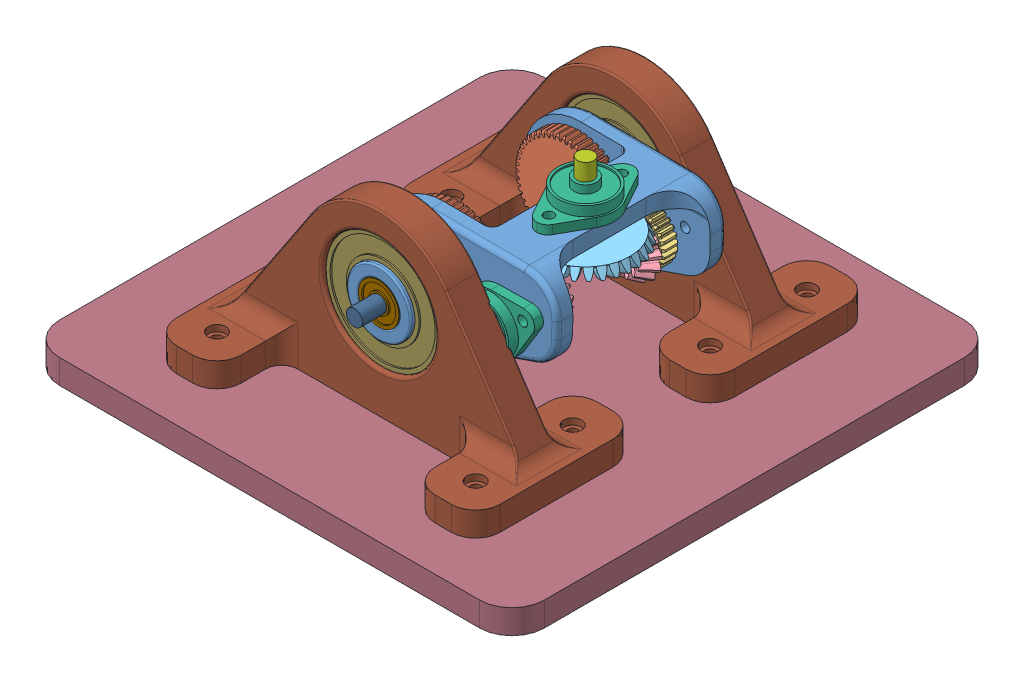
SolidWorks assembly ASSEMBLY Full Design 5th Attempt - Jaw Attach, configuration Default. Lengths in mm.
Overall size (300 144.17 300).
25 component instances, 13 part files, 62 mates.
Components (placement in the parent):
- Main Case-1: Main Case [Default] at (-15.1172 135.8372 30.5077) x (0.999965 -0.008399 0) z (0 0 1) size (115 70 165)
- Secondary Big Spur Gear-1: Secondary Big Spur Gear [Default] at (-15.1172 135.8372 45.5077) x (0.223812 0.974632 0) z (0 0 1) size (62.4 62.32 10)
- Secondary Big Spur Gear-2: Secondary Big Spur Gear [Default] at (-15.1172 135.8372 120.5077) x (-0.440646 0.897681 0) z (0 0 1) size (62.4 62.32 10)
- Main Spur Gear - Copy-1: Main Spur Gear - Copy [Default] at (29.8812 135.4592 120.5077) x (-0.557244 0.830349 0) z (0 0 1) size (32.38 32.33 10)
- Main Spur Gear - Copy-2: Main Spur Gear - Copy [Default] at (29.8812 135.4592 45.5077) x (-0.968851 0.247643 0) z (0 0 1) size (32.38 32.33 10)
- Secondary Bevel Gear-1: Secondary Bevel Gear [Default] at (29.8812 135.4592 53.1298) x (0.968851 -0.247643 0) z (-0.247643 -0.968851 0) size (38.46 39.84 38.26)
- Secondary Bevel Gear-2: Secondary Bevel Gear [Default] at (29.8812 135.4592 112.8856) x (-0.557244 0.830349 0) z (-0.830349 -0.557244 0) size (38.46 39.84 38.26)
- Secondary Main Bevel Gear-1: Secondary Main Bevel Gear [Default] at (30.0267 152.7791 83.0077) x (-0.999724 0.008397 -0.02196) z (-0.021959 0.000184 0.999759) size (61.95 69.28 62)
- Main Slewing Bearing-1: Main Slewing Bearing [Default] at (30.1752 170.458 83.0077) x (0 0 -1) z (0.999965 -0.008399 0) size (60 15.5 36)
- Secondary Gear Shaft-1: Secondary Gear Shaft [Default] at (30.3944 196.5599 83.0077) x (0.999724 -0.008397 0.02196) z (0.021959 -0.000184 -0.999759) size (10 46 10)
- Secondary Gear Shaft Horizontal-1: Secondary Gear Shaft Horizontal [Default] at (29.8812 135.4592 151.977) x (0.557244 -0.830349 0) z (0.830349 0.557244 0) size (10 46 10)
- Secondary Gear Shaft Horizontal-3: Secondary Gear Shaft Horizontal [Default] at (29.8812 135.4592 14.0383) x (-0.968851 0.247643 0) z (0.247643 0.968851 0) size (10 46 10)
- Main Slewing Bearing-2: Main Slewing Bearing [Default] at (29.8812 135.4592 30.5077) x (0.870194 0.492709 0) z (-0.492709 0.870194 0) size (60 15.5 36)
- Main Slewing Bearing-3: Main Slewing Bearing [Default] at (29.8812 135.4592 135.5077) x (0.870194 0.492709 0) z (0.492709 -0.870194 0) size (60 15.5 36)
- Main Bearing-1: Main Bearing [Default] at (-15.1172 135.8372 130.5077) size (25 25 10)
- Main Bearing-2: Main Bearing [Default] at (-15.1172 135.8372 35.5077) size (25 25 10)
- Secondary Gear Shaft Horizontal Back-1: Secondary Gear Shaft Horizontal Back [Default] at (-15.1172 135.8372 -14.4923) x (0.223812 0.974632 0) z (0.974632 -0.223812 0) size (10 65 10)
- Secondary Gear Shaft Horizontal Back-2: Secondary Gear Shaft Horizontal Back [Default] at (-15.1172 135.8372 180.5077) x (0.440646 -0.897681 0) z (0.897681 0.440646 0) size (10 65 10)
- Main Bearing-3: Main Bearing [Default] at (-15.1172 135.8372 160.5077) size (25 25 10)
- Main Bearing-4: Main Bearing [Default] at (-15.1172 135.8372 5.5077) x (0.957621 -0.288033 0) z (0 0 1) size (25 25 10)
- Main Holder-1: Main Holder [Default] at (-15.1172 135.8372 155.5077) size (200 110 100)
- Main Holder-2: Main Holder [Default] at (-15.1172 135.8372 10.5077) size (200 110 100)
- Main Bearing Big-1: Main Bearing Big [Default] at (-15.1172 135.8372 155.5077) size (70 70 15)
- Main Bearing Big-2: Main Bearing Big [Default] at (-15.1172 135.8372 10.5077) size (70 70 15)
- Bottom Plate-1: Bottom Plate [Default] at (-15.1172 60.8372 83.0077) x (0 0 1) z (-1 0 0) size (300 15 300)
Mates (geometry in assembly coordinates):
- Concentric1: concentric aligned: cylinder of Main Case-1 through (-15.1172 135.8372 125.5077) axis (0 0 1) radius 12.5; cylinder of Secondary Big Spur Gear-2 through (-15.1172 135.8372 115.5077) axis (0 0 1) radius 5
- Coincident1: coincident anti-aligned: plane of Main Case-1 through (-15.1172 135.8372 125.5077) normal (0 0 -1); plane of Secondary Big Spur Gear-2 through (-15.1172 135.8372 125.5077) normal (0 0 1)
- Concentric2: concentric anti-aligned: cylinder of Main Case-1 through (-15.1172 135.8372 40.5077) axis (0 0 -1) radius 12.5; cylinder of Secondary Big Spur Gear-1 through (-15.1172 135.8372 40.5077) axis (0 0 1) radius 5
- Coincident2: coincident anti-aligned: plane of Main Case-1 through (-15.1172 135.8372 40.5077) normal (0 0 1); plane of Secondary Big Spur Gear-1 through (-15.1172 135.8372 40.5077) normal (0 0 -1)
- Concentric3: concentric anti-aligned: cylinder of Main Case-1 through (29.8812 135.4592 40.5077) axis (0 0 -1) radius 5; cylinder of Main Spur Gear - Copy-2 through (29.8812 135.4592 40.5077) axis (0 0 1) radius 5
- Coincident3: coincident anti-aligned: plane of Main Case-1 through (-15.1172 135.8372 40.5077) normal (0 0 1); plane of Main Spur Gear - Copy-2 through (29.8812 135.4592 40.5077) normal (0 0 -1)
- GearMate1: gear = 60 : 30 mm: circle of Main Spur Gear - Copy-2; circle of Secondary Big Spur Gear-1
- Concentric5: concentric aligned: cylinder of Main Case-1 through (29.8812 135.4592 125.5077) axis (0 0 1) radius 5; cylinder of Main Spur Gear - Copy-1 through (29.8812 135.4592 115.5077) axis (0 0 1) radius 5
- Coincident4: coincident anti-aligned: plane of Main Case-1 through (-15.1172 135.8372 125.5077) normal (0 0 -1); plane of Main Spur Gear - Copy-1 through (29.8812 135.4592 125.5077) normal (0 0 1)
- GearMate2: gear = 60 : 30 mm: circle of Main Spur Gear - Copy-1; circle of Secondary Big Spur Gear-2
- Concentric7: concentric aligned: cylinder of Main Case-1 through (29.8812 135.4592 40.5077) axis (0 0 -1) radius 5; cylinder of Secondary Bevel Gear-1 through (29.8812 135.4592 62.5883) axis (0 0 -1) radius 5
- Coincident5: coincident aligned: plane of Main Spur Gear - Copy-2 through (30.0854 128.182 40.5077) normal (0.247643 0.968851 0); plane of Secondary Bevel Gear-1 through (26.21 129.1726 62.5883) normal (0.247643 0.968851 0)
- Concentric8: concentric aligned: cylinder of Main Spur Gear - Copy-1 through (29.8812 135.4592 115.5077) axis (0 0 1) radius 5; cylinder of Secondary Bevel Gear-2 through (29.8812 135.4592 103.4271) axis (0 0 1) radius 5
- Coincident6: coincident aligned: plane of Main Spur Gear - Copy-1 through (25.1833 129.8978 115.5077) normal (0.830349 0.557244 0); plane of Secondary Bevel Gear-2 through (25.1833 129.8978 103.4271) normal (0.830349 0.557244 0)
- Concentric9: concentric aligned: cylinder of Main Case-1 through (29.5872 100.4605 83.0077) axis (0.008399 0.999965 0) radius 5; cylinder of Secondary Main Bevel Gear-1 through (29.9744 146.5548 83.0077) axis (0.008399 0.999965 0) radius 5
- Coincident7: coincident: point of Secondary Bevel Gear-1; point of Secondary Main Bevel Gear-1
- Coincident8: coincident: line of Secondary Bevel Gear-2 through (29.8812 135.4592 83.0077) axis (0.278622 -0.415174 0.866025)
- GearMate3: gear = 34.5 : 60 mm: circle of Secondary Main Bevel Gear-1; circle of Secondary Bevel Gear-1
- GearMate4: gear = 60 : 34.5 mm: circle of Secondary Bevel Gear-2; circle of Secondary Main Bevel Gear-1
- Concentric11: concentric aligned: cylinder of Main Case-1 through (29.5872 100.4605 83.0077) axis (0.008399 0.999965 0) radius 5; cylinder of Main Slewing Bearing-1 through (30.1752 170.458 83.0077) axis (0.008399 0.999965 0) radius 5
- Concentric12: concentric anti-aligned: cylinder of Main Case-1 through (30.1752 170.458 60.5077) axis (0.008399 0.999965 0) radius 3; cylinder of Main Slewing Bearing-1 through (30.2214 175.9578 60.5077) axis (-0.008399 -0.999965 0) radius 3
- Coincident9: coincident anti-aligned: plane of Main Case-1 through (-14.8232 170.8359 40.5077) normal (0.008399 0.999965 0); plane of Main Slewing Bearing-1 through (30.1752 170.458 83.0077) normal (-0.008399 -0.999965 0)
- Concentric13: concentric aligned: cylinder of Main Slewing Bearing-1 through (30.1752 170.458 83.0077) axis (0.008399 0.999965 0) radius 5; cylinder of Secondary Gear Shaft-1 through (30.0081 150.5615 83.0077) axis (0.008399 0.999965 0) radius 5
- Coincident10: coincident aligned: plane of Secondary Main Bevel Gear-1 through (49.7552 150.3956 83.4415) normal (-0.008399 -0.999965 0); plane of Secondary Gear Shaft-1 through (30.0081 150.5615 83.0077) normal (-0.008399 -0.999965 0)
- Coincident11: coincident aligned: plane of Secondary Main Bevel Gear-1 through (31.8732 146.5388 87.6331) normal (-0.999724 0.008397 -0.02196); plane of Secondary Gear Shaft-1 through (32.0256 160.5449 86.0509) normal (-0.999724 0.008397 -0.02196)
- Concentric14: concentric aligned: cylinder of Secondary Bevel Gear-1 through (29.8812 135.4592 62.5883) axis (0 0 -1) radius 5; cylinder of Secondary Gear Shaft Horizontal-3 through (29.8812 135.4592 60.0383) axis (0 0 -1) radius 5
- Coincident12: coincident aligned: plane of Secondary Bevel Gear-1 through (20.9094 137.7525 60.0383) normal (0 0 1); plane of Secondary Gear Shaft Horizontal-3 through (29.8812 135.4592 60.0383) normal (0 0 1)
- Coincident15: coincident aligned: plane of Secondary Bevel Gear-1 through (26.8087 131.5147 62.5883) normal (0.968851 -0.247643 0); plane of Secondary Gear Shaft Horizontal-3 through (27.2006 133.048 50.0383) normal (0.968851 -0.247643 0)
- Concentric15: concentric aligned: cylinder of Secondary Bevel Gear-2 through (29.8812 135.4592 103.4271) axis (0 0 1) radius 5; cylinder of Secondary Gear Shaft Horizontal-1 through (29.8812 135.4592 105.977) axis (0 0 1) radius 5
- Coincident16: coincident aligned: plane of Secondary Bevel Gear-2 through (35.0414 127.77 105.977) normal (0 0 -1); plane of Secondary Gear Shaft Horizontal-1 through (29.8812 135.4592 105.977) normal (0 0 -1)
- Coincident17: coincident aligned: plane of Secondary Bevel Gear-2 through (27.1906 131.2449 103.4271) normal (-0.557244 0.830349 0); plane of Secondary Gear Shaft Horizontal-1 through (28.5046 132.1268 115.977) normal (-0.557244 0.830349 0)
- Concentric16: concentric aligned: cylinder of Secondary Gear Shaft Horizontal-3 through (29.8812 135.4592 60.0383) axis (0 0 -1) radius 5; cylinder of Main Slewing Bearing-2 through (29.8812 135.4592 30.5077) axis (0 0 -1) radius 5
- Coincident18: coincident anti-aligned: plane of Main Case-1 through (-15.1172 135.8372 30.5077) normal (0 0 -1); plane of Main Slewing Bearing-2 through (29.8812 135.4592 30.5077) normal (0 0 1)
- Concentric17: concentric anti-aligned: cylinder of Main Case-1 through (49.4606 146.5452 135.5077) axis (0 0 -1) radius 3; cylinder of Main Slewing Bearing-2 through (49.4606 146.5452 25.0077) axis (0 0 1) radius 3
- Concentric18: concentric aligned: cylinder of Secondary Gear Shaft Horizontal-1 through (29.8812 135.4592 105.977) axis (0 0 1) radius 5; cylinder of Main Slewing Bearing-3 through (29.8812 135.4592 135.5077) axis (0 0 1) radius 5
- Concentric19: concentric aligned: cylinder of Main Case-1 through (49.4606 146.5452 135.5077) axis (0 0 -1) radius 3; cylinder of Main Slewing Bearing-3 through (49.4606 146.5452 141.0077) axis (0 0 -1) radius 3
- Coincident19: coincident anti-aligned: plane of Main Case-1 through (-15.1172 135.8372 135.5077) normal (0 0 1); plane of Main Slewing Bearing-3 through (29.8812 135.4592 135.5077) normal (0 0 -1)
- Concentric20: concentric anti-aligned: cylinder of Main Case-1 through (-15.1172 135.8372 125.5077) axis (0 0 1) radius 12.5; cylinder of Main Bearing-1 through (-15.1172 135.8372 135.5077) axis (0 0 -1) radius 12.5
- Coincident20: coincident aligned: plane of Main Case-1 through (-15.1172 135.8372 135.5077) normal (0 0 1); plane of Main Bearing-1 through (-15.1172 135.8372 135.5077) normal (0 0 1)
- Concentric21: concentric aligned: cylinder of Main Case-1 through (-15.1172 135.8372 40.5077) axis (0 0 -1) radius 12.5; cylinder of Main Bearing-2 through (-15.1172 135.8372 40.5077) axis (0 0 -1) radius 5
- Coincident21: coincident aligned: plane of Main Case-1 through (-15.1172 135.8372 30.5077) normal (0 0 -1); plane of Main Bearing-2 through (-15.1172 135.8372 30.5077) normal (0 0 -1)
- Concentric22: concentric aligned: cylinder of Main Bearing-2 through (-15.1172 135.8372 40.5077) axis (0 0 -1) radius 5; cylinder of Secondary Gear Shaft Horizontal Back-1 through (-15.1172 135.8372 50.5077) axis (0 0 -1) radius 5
- Coincident22: coincident aligned: plane of Secondary Big Spur Gear-1 through (-15.1172 135.8372 50.5077) normal (0 0 1); plane of Secondary Gear Shaft Horizontal Back-1 through (-15.1172 135.8372 50.5077) normal (0 0 1)
- Coincident23: coincident aligned: plane of Secondary Big Spur Gear-1 through (-20.0312 134.9136 40.5077) normal (0.223812 0.974632 0); plane of Secondary Gear Shaft Horizontal Back-1 through (-18.4887 134.5594 40.5077) normal (0.223812 0.974632 0)
- Concentric23: concentric anti-aligned: cylinder of Main Bearing-1 through (-15.1172 135.8372 135.5077) axis (0 0 -1) radius 5; cylinder of Secondary Gear Shaft Horizontal Back-2 through (-15.1172 135.8372 115.5077) axis (0 0 1) radius 5
- Coincident24: coincident aligned: plane of Secondary Big Spur Gear-2 through (-15.1172 135.8372 115.5077) normal (0 0 -1); plane of Secondary Gear Shaft Horizontal Back-2 through (-15.1172 135.8372 115.5077) normal (0 0 -1)
- Coincident25: coincident aligned: plane of Secondary Big Spur Gear-2 through (-18.3496 132.0225 115.5077) normal (-0.440646 0.897681 0); plane of Secondary Gear Shaft Horizontal Back-2 through (-16.929 132.7199 125.5077) normal (-0.440646 0.897681 0)
- Concentric24: concentric anti-aligned: cylinder of Main Case-1 through (-15.1172 135.8372 125.5077) axis (0 0 1) radius 12.5; cylinder of Main Bearing-3 through (-15.1172 135.8372 165.5077) axis (0 0 -1) radius 12.5
- Coincident26: coincident aligned: plane of Main Case-1 through (-15.1172 135.8372 165.5077) normal (0 0 1); plane of Main Bearing-3 through (-15.1172 135.8372 165.5077) normal (0 0 1)
- Concentric25: concentric aligned: cylinder of Main Case-1 through (-15.1172 135.8372 40.5077) axis (0 0 -1) radius 12.5; cylinder of Main Bearing-4 through (-15.1172 135.8372 10.5077) axis (0 0 -1) radius 12.5
- Coincident27: coincident aligned: plane of Main Case-1 through (-15.1172 135.8372 0.5077) normal (0 0 -1); plane of Main Bearing-4 through (-15.1172 135.8372 0.5077) normal (0 0 -1)
- Concentric26: concentric aligned: cylinder of Main Holder-1 through (-15.1172 135.8372 205.5077) axis (0 0 -1) radius 35; cylinder of Main Bearing Big-1 through (-15.1172 135.8372 163.0077) axis (0 0 -1) radius 35
- Coincident28: coincident aligned: plane of Main Holder-1 through (-15.1172 135.8372 155.5077) normal (0 0 1); plane of Main Bearing Big-1 through (-15.1172 135.8372 155.5077) normal (0 0 1)
- Coincident29: coincident aligned: plane of Main Holder-2 through (-15.1172 135.8372 10.5077) normal (0 0 1); plane of Main Bearing Big-2 through (-15.1172 135.8372 10.5077) normal (0 0 1)
- Concentric27: concentric aligned: cylinder of Main Holder-2 through (-15.1172 135.8372 60.5077) axis (0 0 -1) radius 35; cylinder of Main Bearing Big-2 through (-15.1172 135.8372 18.0077) axis (0 0 -1) radius 35
- Concentric28: concentric aligned: cylinder of Main Case-1 through (-15.1172 135.8372 165.5077) axis (0 0 -1) radius 20; cylinder of Main Bearing Big-1 through (-15.1172 135.8372 163.0077) axis (0 0 -1) radius 20
- Concentric29: concentric anti-aligned: cylinder of Main Case-1 through (-15.1172 135.8372 0.5077) axis (0 0 1) radius 20; cylinder of Main Bearing Big-2 through (-15.1172 135.8372 18.0077) axis (0 0 -1) radius 20
- Coincident30: coincident aligned: plane of Main Case-1 through (-15.1172 135.8372 165.5077) normal (0 0 1); plane of Main Holder-1 through (-15.1172 135.8372 165.5077) normal (0 0 1)
- Coincident31: coincident aligned: plane of Main Case-1 through (-15.1172 135.8372 0.5077) normal (0 0 -1); plane of Main Holder-2 through (-15.1172 135.8372 0.5077) normal (0 0 -1)
- Concentric30: concentric aligned: cylinder of Main Holder-2 through (64.8828 90.8372 -19.4923) axis (0 1 0) radius 3.2; cylinder of Bottom Plate-1 through (64.8828 75.8372 -19.4923) axis (0 1 0) radius 3
- Coincident32: coincident anti-aligned: plane of Main Holder-2 through (-115.1172 75.8372 20.5077) normal (0 -1 0); plane of Bottom Plate-1 through (-15.1172 75.8372 83.0077) normal (0 1 0)
- Concentric32: concentric aligned: cylinder of Main Holder-1 through (64.8828 90.8372 185.5077) axis (0 1 0) radius 3.2; circle of Bottom Plate-1
